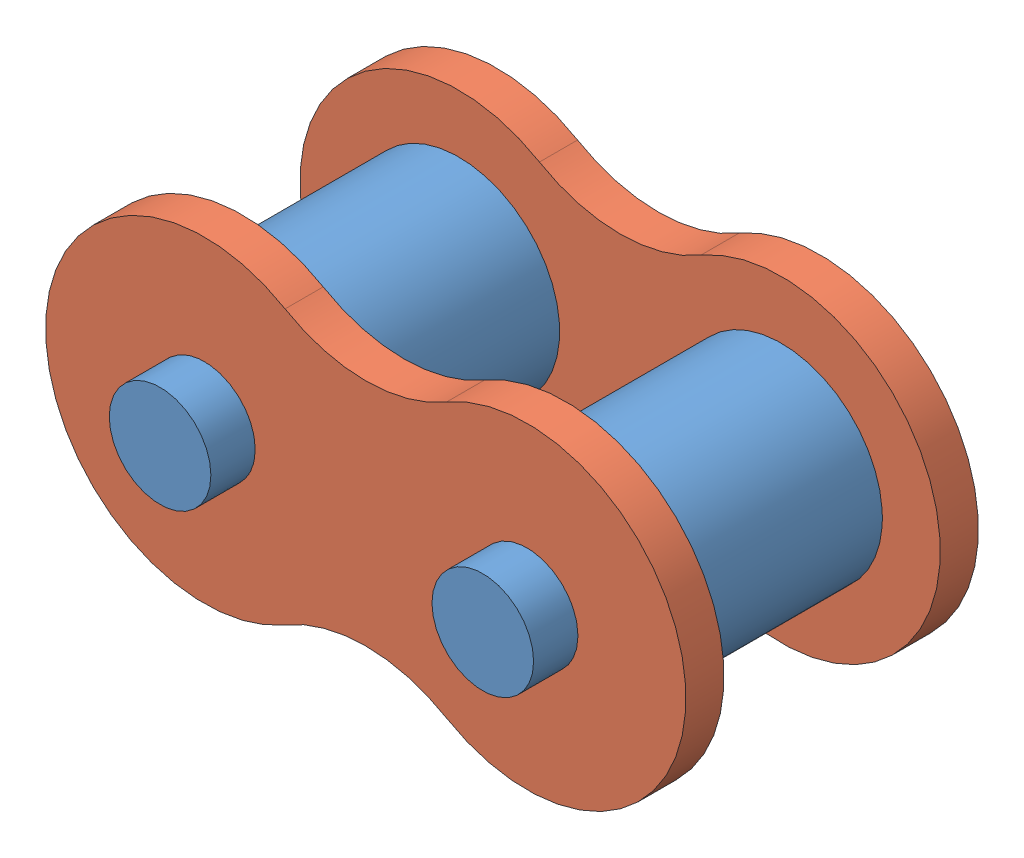
SolidWorks assembly links sa7, configuration Default. Lengths in mm.
Overall size (50.4 25 30).
4 component instances, 2 part files, 7 mates.
Components (placement in the parent):
- chain roller-1: chain roller [Default] at (-46.6108 74.88 -8.51) size (15.88 15.88 30)
- chain roller-2: chain roller [Default] at (-21.2108 74.88 -8.51) size (15.88 15.88 30)
- plates-1: plates [Default] at (-46.6108 74.88 8.51) size (50.4 25 3)
- plates-2: plates [Default] at (-46.6108 74.88 -11.51) size (50.4 25 3)
Mates (geometry in assembly coordinates):
- Concentric1: concentric aligned: cylinder of chain roller-1 through (-46.6108 74.88 15) axis (0 0 -1) radius 4; cylinder of plates-1 through (-46.6108 74.88 11.51) axis (0 0 -1) radius 4
- Coincident1: coincident anti-aligned: plane of chain roller-1 through (-46.6108 74.88 8.51) normal (0 0 1); plane of plates-1 through (-40.2608 64.1131 8.51) normal (0 0 -1)
- Concentric2: concentric aligned: cylinder of chain roller-2 through (-21.2108 74.88 15) axis (0 0 -1) radius 4; cylinder of plates-1 through (-21.2108 74.88 11.51) axis (0 0 -1) radius 4
- Coincident2: coincident anti-aligned: plane of chain roller-2 through (-21.2108 74.88 8.51) normal (0 0 1); plane of plates-1 through (-40.2608 64.1131 8.51) normal (0 0 -1)
- Coincident3: coincident anti-aligned: plane of chain roller-1 through (-46.6108 74.88 -8.51) normal (0 0 -1); plane of plates-2 through (-40.2608 64.1131 -8.51) normal (0 0 1)
- Concentric3: concentric aligned: cylinder of chain roller-1 through (-46.6108 74.88 15) axis (0 0 -1) radius 4; cylinder of plates-2 through (-46.6108 74.88 -8.51) axis (0 0 -1) radius 4
- Symmetric1: symmetric aligned: plane of plates-1 through (-40.2608 64.1131 11.51) normal (0 0 1); plane of plates-2 through (-40.2608 64.1131 -11.51) normal (0 0 -1)
